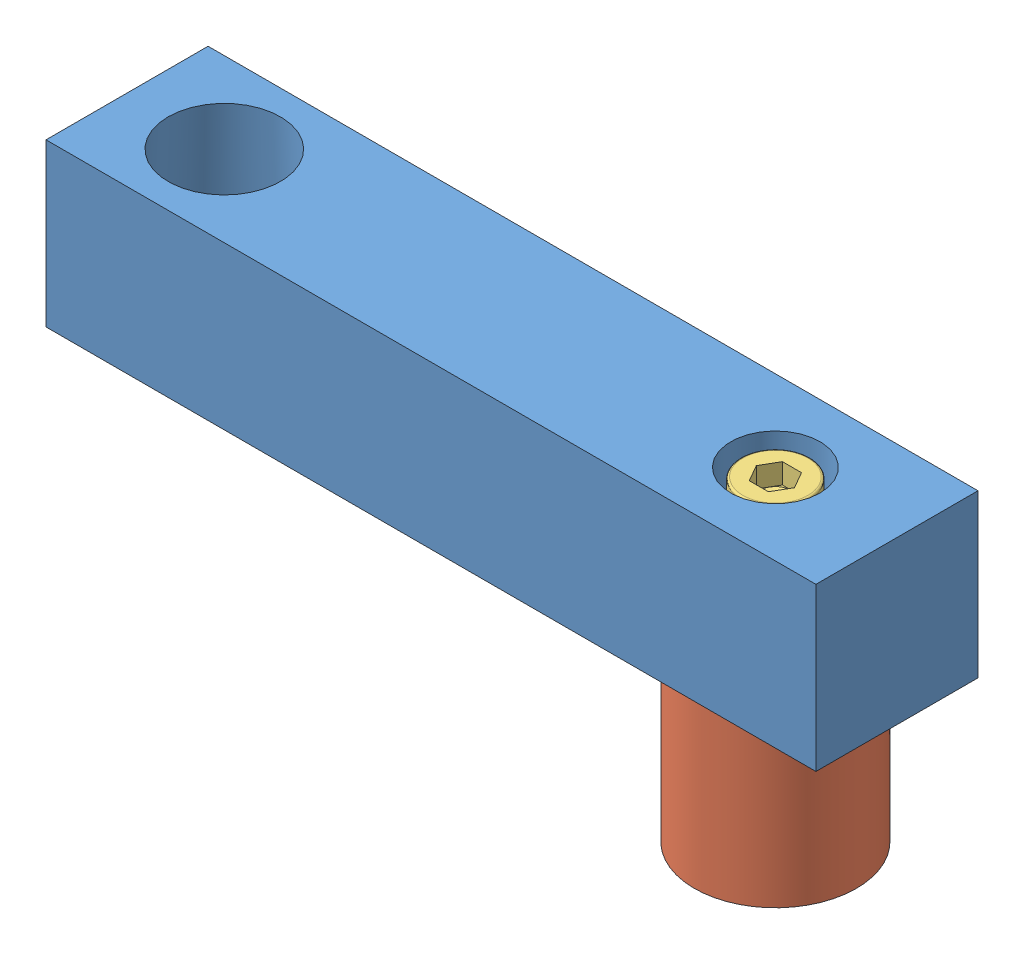
SolidWorks assembly assemb_braco_v3, configuration Default. Lengths in mm.
Overall size (95 40 21.92).
3 component instances, 3 part files, 4 mates.
Components (placement in the parent):
- clamping_arm_sp_v3-1: clamping_arm_sp_v3 [Default] at (-11.0842 57.292 80.6201) x (1 0 0) z (0 1 0) size (95 20 20)
- contact_end_full-1: contact_end_full [Default] at (56.9158 17.292 80.6201) x (0.994886 0 -0.101006) z (0.101006 0 0.994886) size (20 25 20)
- socket head cap screw_iso-2: socket head cap screw_iso [ISO 4762 M5 x 16 - 16N] at (56.9158 56.292 80.6201) x (0 -1 0) z (0 0 1) size (21 8.5 8.5)
Mates (geometry in assembly coordinates):
- Concentric1: concentric anti-aligned: cylinder of clamping_arm_sp_v3-1 through (56.9158 42.292 80.6201) axis (0 -1 0) radius 7.5; cylinder of contact_end_full-1 through (56.9158 37.292 80.6201) axis (0 1 0) radius 7.5
- Coincident1: coincident anti-aligned: plane of clamping_arm_sp_v3-1 through (56.9158 42.292 80.6201) normal (0 -1 0); plane of contact_end_full-1 through (56.9158 42.292 80.6201) normal (0 1 0)
- Concentric3: concentric anti-aligned: cylinder of clamping_arm_sp_v3-1 through (56.9158 57.292 80.6201) axis (0 -1 0) radius 2.75; cylinder of socket head cap screw_iso-2 through (56.9158 88.042 80.6201) axis (0 1 0) radius 4.25
- Coincident3: coincident anti-aligned: plane of clamping_arm_sp_v3-1 through (56.9158 51.292 80.6201) normal (0 1 0); plane of socket head cap screw_iso-2 through (61.1658 51.292 80.6201) normal (0 -1 0)
